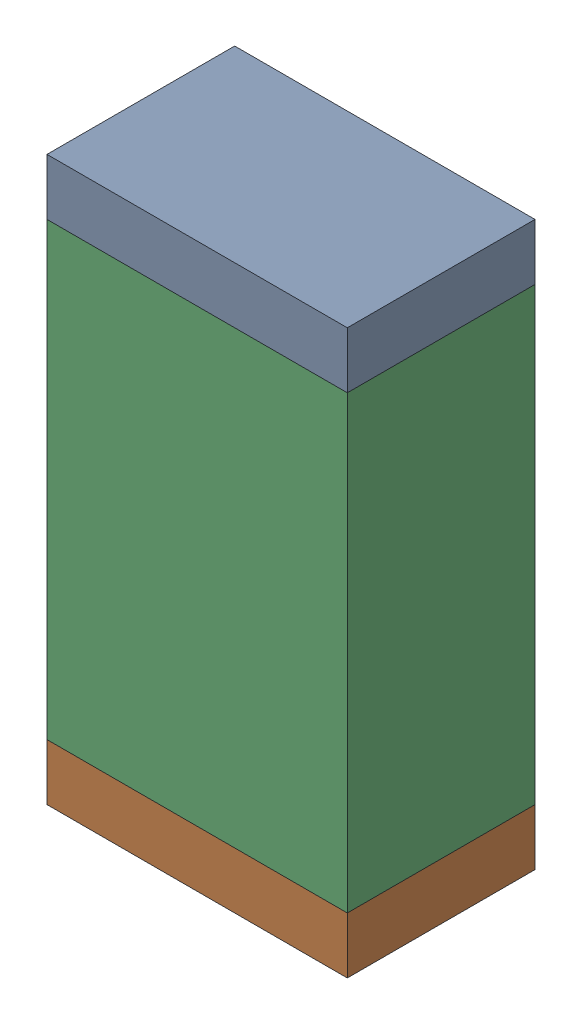
SolidWorks assembly R41, configuration Default. Lengths in mm.
Overall size (0.8 1.5 0.5).
6 component instances, 2 part files, 0 mates.
Components (placement in the parent):
- 810156592-1: 810156592 [Default] at (117.15 54.075 0) size (0.8 0.15 0.5)
  - Extruded_7-1: Extruded_7 [Default] at origin size (0.8 0.15 0.5)
- 810156592-2: 810156592 [Default] at (117.15 52.725 0) size (0.8 0.15 0.5)
  - Extruded_7-1: Extruded_7 [Default] at origin size (0.8 0.15 0.5)
- 810156976-1: 810156976 [Default] at (117.15 53.4 0) size (0.8 1.2 0.5)
  - Extruded_6-1: Extruded_6 [Default] at origin size (0.8 1.2 0.5)
